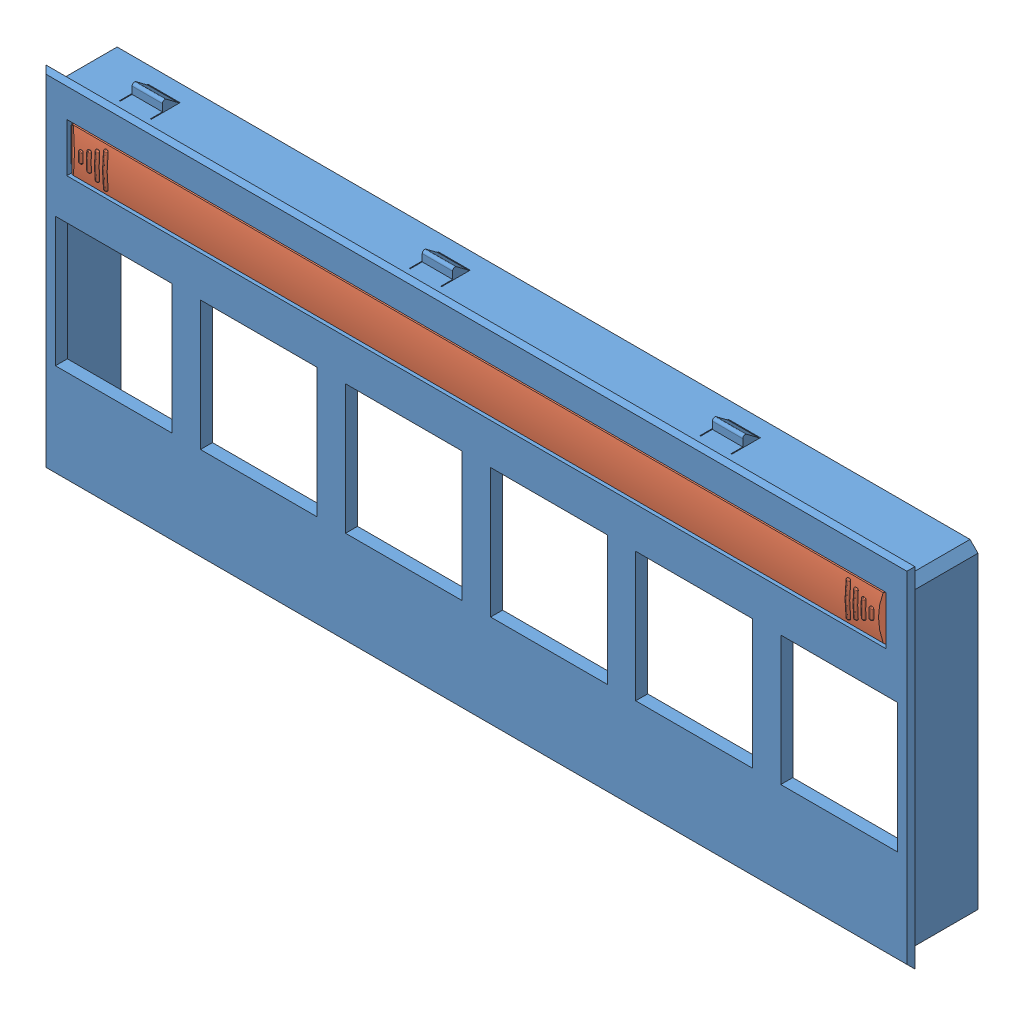
SolidWorks assembly Keystone-Pannel-6-Module, configuration Standard. Lengths in mm.
Overall size (108.7 43.6 8.85).
2 component instances, 2 part files, 6 mates.
Components (placement in the parent):
- 19-Keystone-Pannel-Einsatz-1: 19-Keystone-Pannel-Einsatz [Standard] at (-54.35 -21.8 -8.4) size (108.7 43.6 8.4)
- 19-Keystone-Pannel-Glas-1: 19-Keystone-Pannel-Glas [Standard] at (-54.1 -7 -1) size (104 5.8 1.45)
Mates (geometry in assembly coordinates):
- Deckungsgleich1: coincident: plane of 19-Keystone-Pannel-Einsatz-1 through (-54.35 -21.8 0) normal (0 0 1); plane of assembly
- Deckungsgleich2: coincident: line of 19-Keystone-Pannel-Einsatz-1 through (0 0 -0.5) axis (-1 0 0); plane of assembly
- Deckungsgleich3: coincident aligned: plane of 19-Keystone-Pannel-Einsatz-1 through (0 -43.6 -8.4) normal (1 0 0); plane of assembly
- Deckungsgleich4: coincident: plane of 19-Keystone-Pannel-Einsatz-1 through (-54.35 -7.15 -1) normal (0 0 1); plane of 19-Keystone-Pannel-Glas-1 through (-54.1 -7 -1) normal (0 0 -1)
- Deckungsgleich5: coincident: plane of 19-Keystone-Pannel-Einsatz-1 through (-105.6 -4.1 0) normal (0 -1 0); plane of 19-Keystone-Pannel-Glas-1 through (-3.1 -4.1 -1) normal (0 1 0)
- Deckungsgleich6: coincident anti-aligned: plane of 19-Keystone-Pannel-Einsatz-1 through (-3.1 -4.1 0) normal (-1 0 0); plane of 19-Keystone-Pannel-Glas-1 through (-3.1 -9.9 -1) normal (1 0 0)
